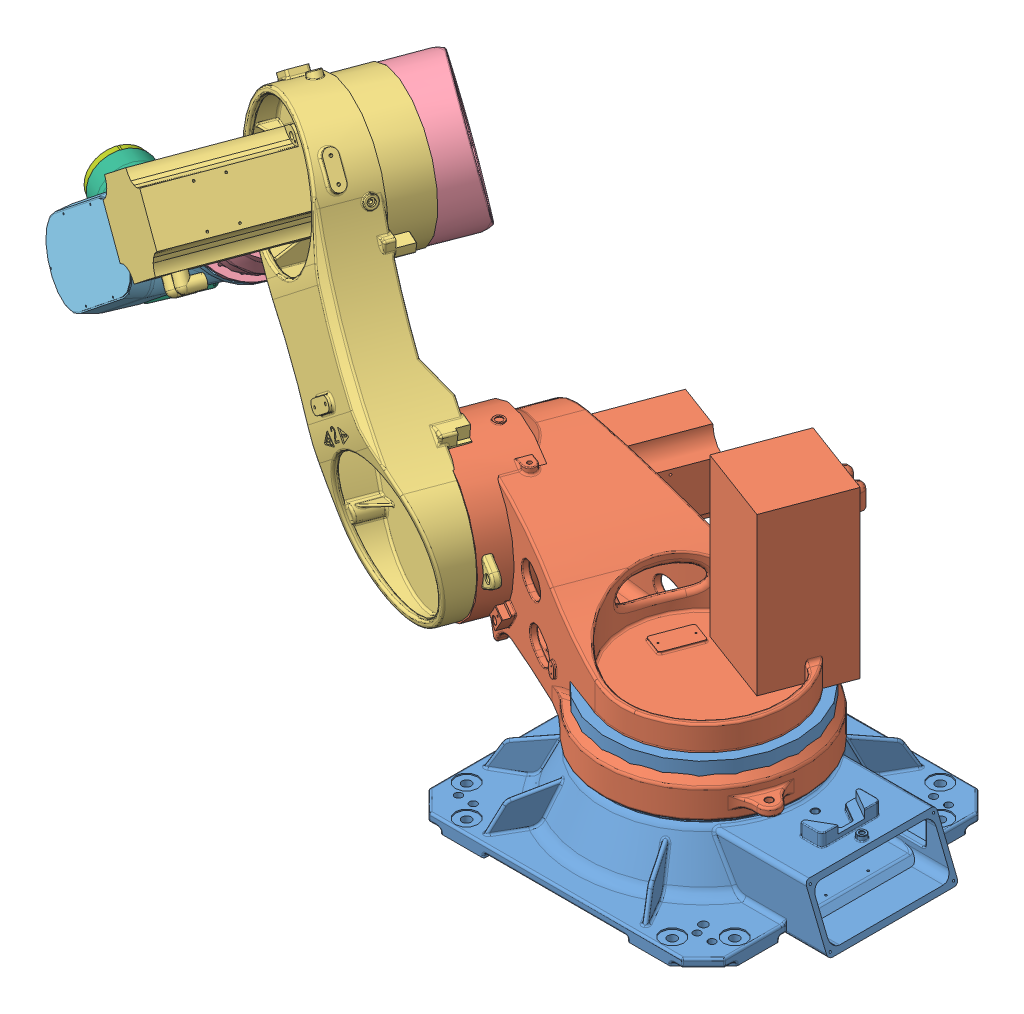
SolidWorks assembly 已解密_机器人SW装配体数模, configuration Default. Lengths in mm.
Overall size (2575.89 1509.62 1358.94).
7 component instances, 7 part files, 15 mates.
Components (placement in the parent):
- 复件 底座^已解密_机器人SW装配体数模-1: 复件 底座^已解密_机器人SW装配体数模 [Default] at origin size (802.07 268.5 704.15) (virtual)
- 复件 转座^已解密_机器人SW装配体数模-1: 复件 转座^已解密_机器人SW装配体数模 [Default] at (0 -10 0) x (0.936779 0 0.349922) z (-0.349922 0 0.936779) size (965 505.2 553.5)
- 复件 大臂^已解密_机器人SW装配体数模-1: 复件 大臂^已解密_机器人SW装配体数模 [Default] at (59.0487 590.3952 22.0569) x (0.483667 0.856402 0.180668) z (-0.349922 0 0.936779) size (562.6 937.68 492.5) (virtual)
- 复件 小臂^已解密_机器人SW装配体数模-1: 复件 小臂^已解密_机器人SW装配体数模 [Default] at (-1326.2634 710.1256 -495.4093) x (0.330636 0.935642 0.123505) z (-0.349922 0 0.936779) size (1128.64 787.3 297.85) (virtual)
- 复件 前臂^已解密_机器人SW装配体数模-1: 复件 前臂^已解密_机器人SW装配体数模 [Default] at (-1322.5703 708.5285 -501.5561) x (0.335666 0.93549 0.110398) z (-0.366455 0.021718 0.930182) size (523.55 412.29 301.01) (virtual)
- 复件 手腕体^已解密_机器人SW装配体数模-1: 复件 手腕体^已解密_机器人SW装配体数模 [Default] at (-2099.5996 -11847.7459 -439.2617) x (0.016164 0.999725 -0.016973) z (0.366455 -0.021718 -0.930182) size (170.78 257.17 141) (virtual)
- 复件 末端法兰^已解密_机器人SW装配体数模-1: 复件 末端法兰^已解密_机器人SW装配体数模 [Default] at (-6403.047 -130.5325 10214.1735) x (0.382532 0.002196 -0.923939) z (0.008782 -0.999961 0.00126) size (125.3 22.14 125.2) (virtual)
Mates (geometry in assembly coordinates):
- 重合1: coincident aligned: plane of 复件 底座^已解密_机器人SW装配体数模-1 through (0 0 0) normal (0 0 1); plane of assembly through (0 0 0) normal (0 0 1)
- 重合2: coincident aligned: plane of 复件 底座^已解密_机器人SW装配体数模-1 through (0 0 0) normal (0 1 0); plane of assembly through (0 0 0) normal (0 1 0)
- 重合3: coincident aligned: plane of 复件 底座^已解密_机器人SW装配体数模-1 through (0 0 0) normal (1 0 0); plane of assembly through (0 0 0) normal (1 0 0)
- 重合4: coincident anti-aligned: plane of 复件 底座^已解密_机器人SW装配体数模-1 through (0 258.5 0) normal (0 1 0); plane of 复件 转座^已解密_机器人SW装配体数模-1 through (0 258.5 0) normal (0 -1 0)
- 同心1: concentric aligned: cylinder of 复件 底座^已解密_机器人SW装配体数模-1 through (0 258.5 0) axis (0 -1 0) radius 225; cylinder of 复件 转座^已解密_机器人SW装配体数模-1 through (0 258.5 0) axis (0 -1 0) radius 189.5
- 重合6: coincident anti-aligned: plane of 复件 转座^已解密_机器人SW装配体数模-1 through (-561.9936 346 75.6272) normal (-0.349922 0 0.936779); plane of 复件 大臂^已解密_机器人SW装配体数模-1 through (-561.9936 346 75.6272) normal (0.349922 0 -0.936779)
- 同心2: concentric anti-aligned: cylinder of 复件 转座^已解密_机器人SW装配体数模-1 through (-332.9434 346 -537.5645) axis (-0.349922 0 0.936779) radius 175; cylinder of 复件 大臂^已解密_机器人SW装配体数模-1 through (-560.244 346 70.9434) axis (0.349922 0 -0.936779) radius 145
- 重合9: coincident anti-aligned: plane of 复件 大臂^已解密_机器人SW装配体数模-1 through (-883.3335 820.628 -159.1603) normal (0.349922 0 -0.936779); plane of 复件 小臂^已解密_机器人SW装配体数模-1 through (-883.3335 820.628 -159.1603) normal (-0.349922 0 0.936779)
- 重合10: coincident anti-aligned: plane of 复件 小臂^已解密_机器人SW装配体数模-1 through (-1609.031 158.2915 -526.3095) normal (-0.724584 -0.633815 -0.270659); plane of 复件 前臂^已解密_机器人SW装配体数模-1 through (-1609.031 158.2915 -526.3095) normal (0.724584 0.633815 0.270659)
- 同心4: concentric aligned: cylinder of 复件 小臂^已解密_机器人SW装配体数模-1 through (-1584.0328 180.1581 -516.9718) axis (-0.724584 -0.633815 -0.270659) radius 121; cylinder of 复件 前臂^已解密_机器人SW装配体数模-1 through (-1603.2343 163.362 -524.1442) axis (-0.724584 -0.633815 -0.270659) radius 121
- 重合12: coincident anti-aligned: plane of 复件 前臂^已解密_机器人SW装配体数模-1 through (-1933.9195 -103.3083 -577.2412) normal (0.366455 -0.021718 -0.930182); plane of 复件 手腕体^已解密_机器人SW装配体数模-1 through (-1933.9195 -103.3083 -577.2412) normal (-0.366455 0.021718 0.930182)
- 同心5: concentric aligned: cylinder of 复件 前臂^已解密_机器人SW装配体数模-1 through (-2050.2857 -96.412 -281.8657) axis (0.366455 -0.021718 -0.930182) radius 79; cylinder of 复件 手腕体^已解密_机器人SW装配体数模-1 through (-1937.851 -103.0754 -567.2617) axis (0.366455 -0.021718 -0.930182) radius 70
- 重合14: coincident anti-aligned: plane of 复件 手腕体^已解密_机器人SW装配体数模-1 through (-2081.8606 -152.7489 -705.3236) normal (-0.930436 -0.008633 -0.366353); plane of 复件 末端法兰^已解密_机器人SW装配体数模-1 through (-2090.8307 -65.6854 -684.5937) normal (0.930436 0.008633 0.366353)
- 同心6: concentric aligned: cylinder of 复件 手腕体^已解密_机器人SW装配体数模-1 through (-2002.1018 -105.5988 -675.0027) axis (0.930436 0.008633 0.366353) radius 66.5; cylinder of 复件 末端法兰^已解密_机器人SW装配体数模-1 through (-2080.0032 -106.3216 -705.6759) axis (0.930436 0.008633 0.366353) radius 62.5
- 同心7: concentric anti-aligned: cylinder of 复件 大臂^已解密_机器人SW装配体数模-1 through (-921.65 820.628 -56.583) axis (0.349922 0 -0.936779) radius 162.5; cylinder of 复件 小臂^已解密_机器人SW装配体数模-1 through (-885.608 820.628 -153.0712) axis (-0.349922 0 0.936779) radius 146.5
